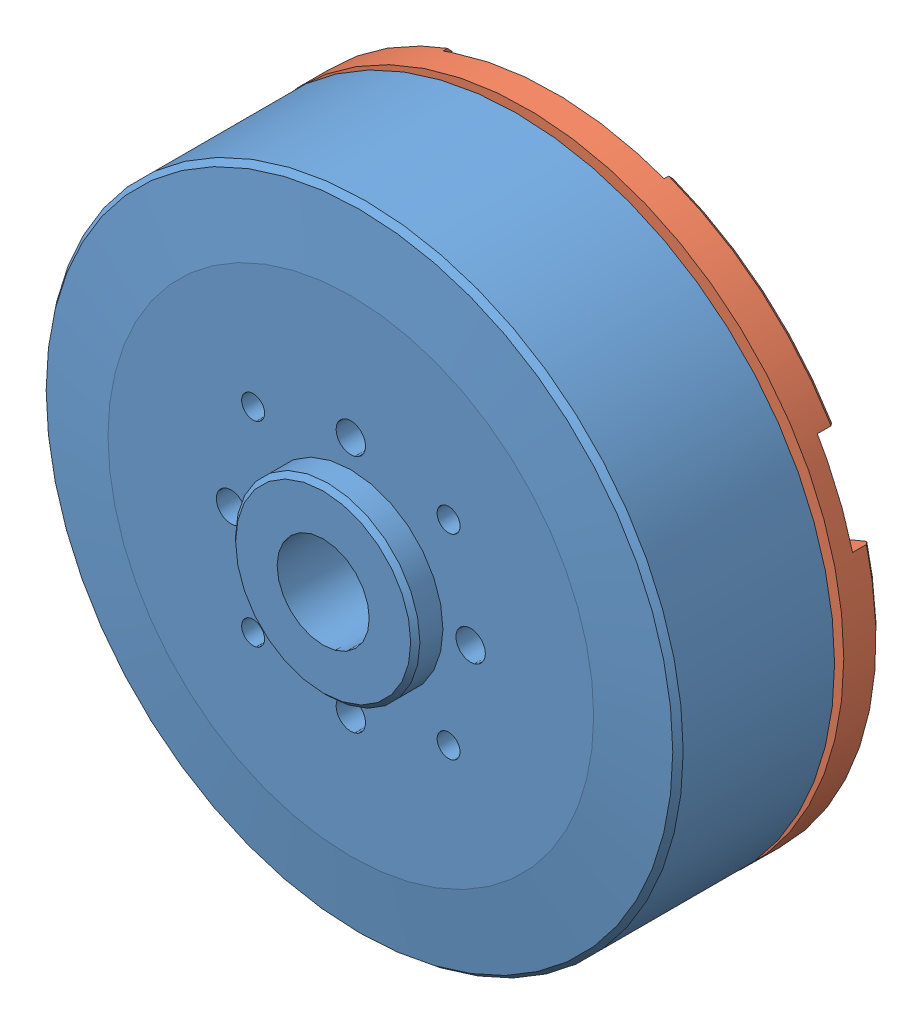
SolidWorks assembly motor, configuration Default. Lengths in mm.
Overall size (69 69 26).
2 component instances, 2 part files, 3 mates.
Components (placement in the parent):
- motor_front-1: motor_front [Default] at origin size (69 69 25)
- motor_rear-1: motor_rear [Default] at (0 0 9) x (-1 0 0) z (0 0 -1) size (69 69 14)
Mates (geometry in assembly coordinates):
- Concentric1: concentric: cylinder of motor_front-1 through (0 0 18) axis (0 0 -1) radius 34.5; cylinder of motor_rear-1 through (0 0 -5) axis (0 0 1) radius 34.5
- Distance2: distance = 1 mm: plane of motor_front-1 through (0 0 0) normal (0 0 -1); plane of motor_rear-1 through (0 0 -1) normal (0 0 1)
- Parallel1: parallel aligned: plane of motor_front-1 through (0 0 0) normal (0 1 0); plane of motor_rear-1 through (0 0 9) normal (0 1 0)
